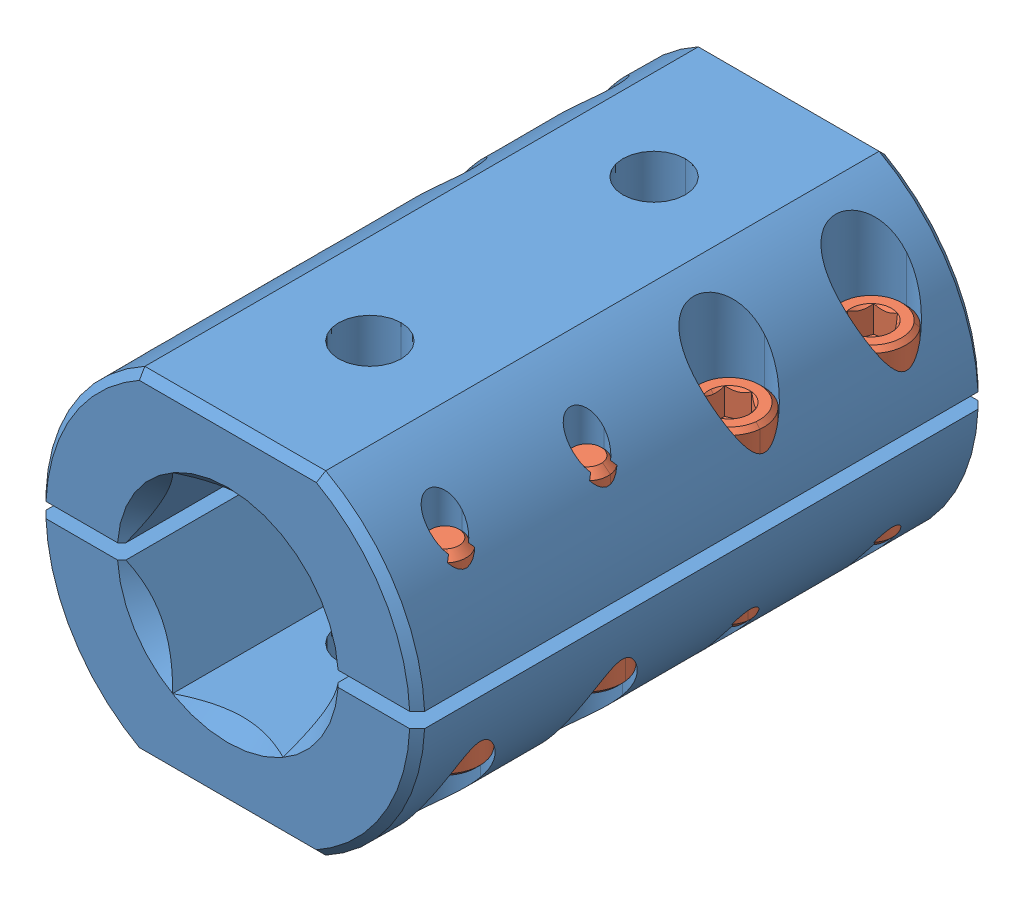
SolidWorks assembly 1_2 Hex Shaft Coupler (217-4008), configuration Default. Lengths in mm.
Overall size (25.76 22.32 38.1).
11 component instances, 2 part files, 0 mates.
Components (placement in the parent):
- 1_2 Hex Shaft Coupler (217-4008).step-1: 1_2 Hex Shaft Coupler (217-4008).step [Default] at origin size (25.76 22.32 38.1)
  - 217-4008-001 Rev1.step-1: 217-4008-001 Rev1.step [Default] at origin size (25.38 10.66 38.1)
  - 217-4008-001 Rev1.step-2: 217-4008-001 Rev1.step [Default] x (1 0 0) z (0 0 -1) size (25.38 10.66 38.1)
  - 217-4008-002 Rev1_91251A108.step-1: 217-4008-002 Rev1_91251A108.step [Default] at (9.7928 7.025 4.7625) x (0.994016 0 -0.109231) z (0 1 0) size (4.65 4.65 12.38)
  - 217-4008-002 Rev1_91251A108.step-2: 217-4008-002 Rev1_91251A108.step [Default] at (9.7928 7.025 14.2875) x (-0.765668 0 -0.643235) z (0 1 0) size (4.65 4.65 12.38)
  - 217-4008-002 Rev1_91251A108.step-3: 217-4008-002 Rev1_91251A108.step [Default] at (-9.7928 7.025 14.2875) x (-0.114094 0 0.99347) z (0 1 0) size (4.65 4.65 12.38)
  - 217-4008-002 Rev1_91251A108.step-4: 217-4008-002 Rev1_91251A108.step [Default] at (-9.7928 7.025 4.7625) x (0.20346 0 0.979083) z (0 1 0) size (4.65 4.65 12.38)
  - 217-4008-002 Rev1_91251A108.step-5: 217-4008-002 Rev1_91251A108.step [Default] at (-9.7928 -7.025 -4.7625) x (0.20346 0 -0.979083) z (0 -1 0) size (4.65 4.65 12.38)
  - 217-4008-002 Rev1_91251A108.step-6: 217-4008-002 Rev1_91251A108.step [Default] at (-9.7928 -7.025 -14.2875) x (-0.114094 0 -0.99347) z (0 -1 0) size (4.65 4.65 12.38)
  - 217-4008-002 Rev1_91251A108.step-7: 217-4008-002 Rev1_91251A108.step [Default] at (9.7928 -7.025 -14.2875) x (-0.765668 0 0.643235) z (0 -1 0) size (4.65 4.65 12.38)
  - 217-4008-002 Rev1_91251A108.step-8: 217-4008-002 Rev1_91251A108.step [Default] at (9.7928 -7.025 -4.7625) x (0.994016 0 0.109231) z (0 -1 0) size (4.65 4.65 12.38)
